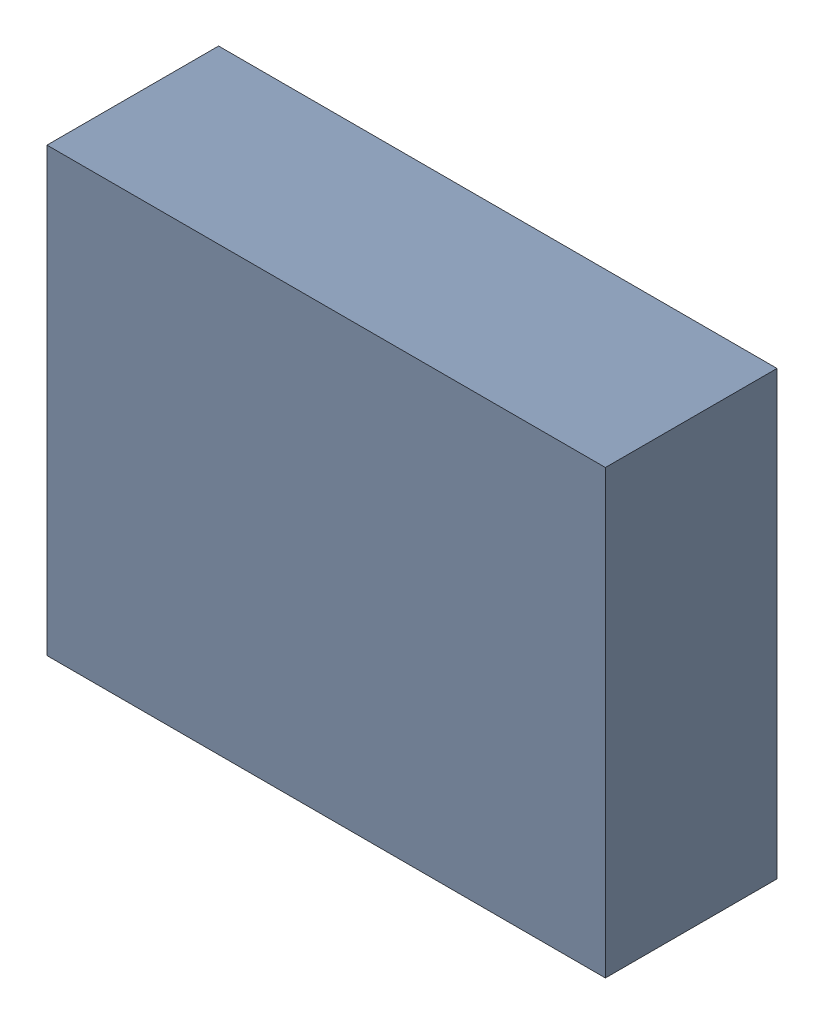
SolidWorks assembly OP3, configuration Default. Lengths in mm.
Overall size (5.04 3.99 1.55).
2 component instances, 1 part files, 0 mates.
Components (placement in the parent):
- 407985952-1: 407985952 [Default] at (55.245 27.051 0.2157) size (5.04 3.99 1.55)
  - Extruded-1: Extruded [Default] at origin size (5.04 3.99 1.55)
